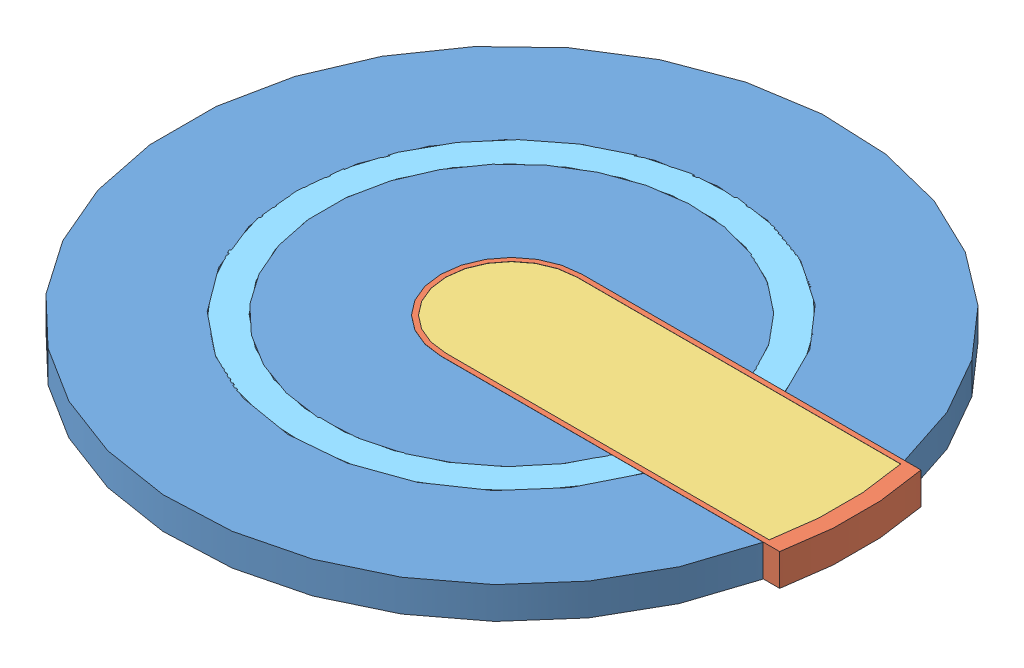
SolidWorks assembly ETA_2, configuration Default. Lengths in mm.
Overall size (308.51 12.95 267).
7 component instances, 6 part files, 5 mates.
Components (placement in the parent):
- Bi_3_m-1: Bi_3_m [Default] at (73.9244 153.8881 205.0769) size (263.91 12.9 267)
- Drawer-1: Drawer [Default] at (61.268 57.9151 88.4061) size (203.59 12.9 57.15)
  - Drawer-1: Drawer [Default] at (12.6564 98.023 116.6708) size (168.57 12.9 57.15)
  - Drawer_Cover-1: Drawer_Cover [Default] at (12.6564 106.923 116.6708) size (160.08 1.95 53.15)
  - Pb-1: Pb [Default] at (12.6564 98.023 116.6708) size (133.5 8.9 53.15)
  - Drawer_Handle-1: Drawer_Handle [Default] at (12.6564 98.923 116.6708) x (1 0 0.000592) z (-0.000592 0 1) size (37.07 7 48)
- Si_2_m-1: Si_2_m [Default] at (73.9244 166.7881 205.0769) x (1 0 0) z (0 -1 0) size (169.84 174 12.9)
Mates (geometry in assembly coordinates):
- Coincident1: coincident aligned: plane of Bi_3_m-1 through (73.9244 166.7881 205.0769) normal (0 1 0); plane of Drawer-1/Drawer_Cover-1 through (73.9244 166.7881 205.0769) normal (0 1 0)
- Coincident2: coincident anti-aligned: plane of Bi_3_m-1 through (156.0978 166.7881 176.5019) normal (0 0 1); plane of ? through (73.9244 153.9381 176.5019) normal (0 0 -1)
- Concentric2: concentric aligned: circle of Bi_3_m-1; circle of ?
- Coincident8: coincident aligned: plane of Bi_3_m-1 through (73.9244 166.7881 205.0769) normal (0 1 0); plane of Si_2_m-1 through (73.9244 166.7881 205.0769) normal (0 1 0)
- Coincident9: coincident anti-aligned: circle of Bi_3_m-1; circle of Si_2_m-1
